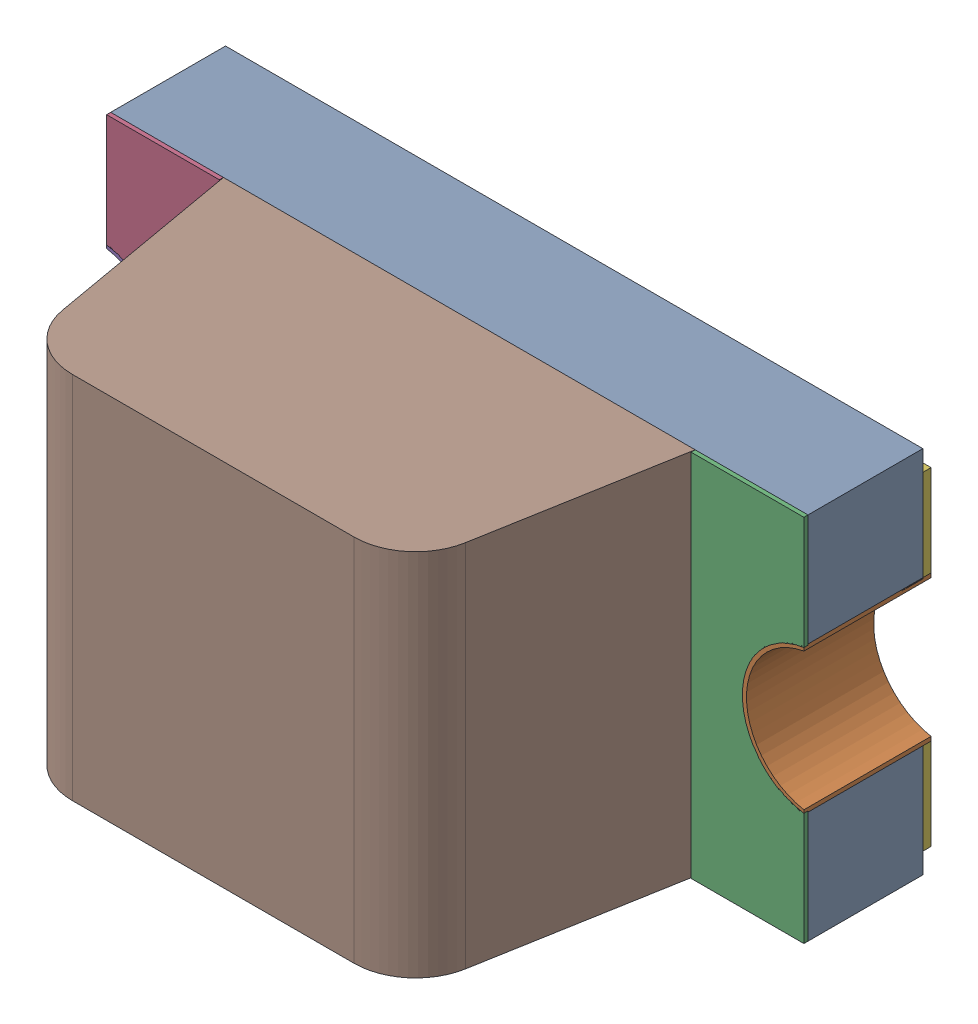
SolidWorks assembly LED2主板_V1.0, configuration 默认. Lengths in mm.
Overall size (1.7 0.9 0.9).
7 component instances, 6 part files, 0 mates.
Components (placement in the parent):
- LED-BLUE-0603-1: LED-BLUE-0603 [默认] at (60.9346 -0.73 0) x (0 -1 0) z (0 0 1) size (0.9 1.7 0.9)
  - User_Library-LTST-C190TBKT_Pad-1: User_Library-LTST-C190TBKT_Pad [默认] at origin size (0.9 1.7 0.28)
  - User_Library-LTST-C190TBKT_Pad005-1: User_Library-LTST-C190TBKT_Pad005 [默认] at origin size (0.35 0.15 0.31)
  - User_Library-LTST-C190TBKT_Pad001-1: User_Library-LTST-C190TBKT_Pad001 [默认] at origin size (0.9 1.7 0.01)
  - User_Library-LTST-C190TBKT_Pad004-1: User_Library-LTST-C190TBKT_Pad004 [默认] at origin size (0.35 0.15 0.31)
  - User_Library-LTST-C190TBKT_Pad003-1: User_Library-LTST-C190TBKT_Pad003 [默认] at origin size (0.8 1.7 0.02)
  - User_Library-LTST-C190TBKT_Lens-1: User_Library-LTST-C190TBKT_Lens [默认] at origin size (0.9 1.15 0.6)
